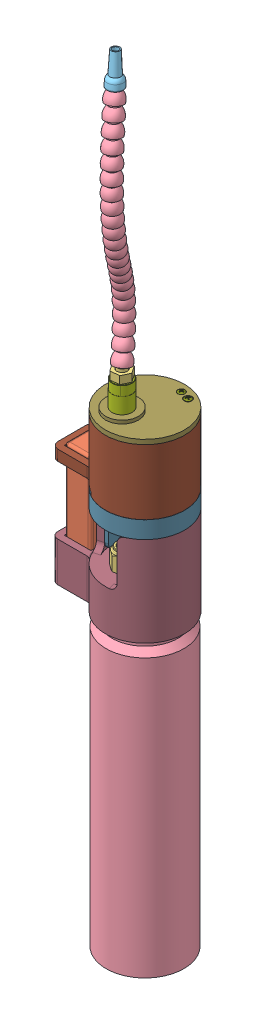
SolidWorks assembly _Robocup_Assembly_Wide_Straw_Water_Bottle_, configuration Default. Lengths in mm.
Overall size (108.2 768.91 103.62).
85 component instances, 35 part files, 77 mates.
Components (placement in the parent):
- SF3218MG Servo-1: SF3218MG Servo [Default] at (-17.653 -62.7888 -19.9) size (54.86 45.72 19.05)
- Servo gear 30t-1: Servo gear 30t [Default] at (-7.993 -20.4688 -10.375) x (-0.381225 0 -0.924482) z (0 1 0) size (25.51 25.6 6)
- Coolant Pipe.stp-1: Coolant Pipe.stp [Default] at (-8.06 46.6882 14.01) x (0.568385 0 0.822762) z (-0.822762 0 0.568385) size (74.23 300.91 26.18)
  - Coolant Bolt.stp-1: Coolant Bolt.stp [Default] x (-1 0 0) z (0 0 1) size (17.61 27.5 15.25)
  - Connectors.stp-1: Connectors.stp [Default] at (-2.2835 3.6671 -0.0362) x (-0.321951 -0.100327 -0.941426) z (0.285439 -0.958386 0.00452) size (18.3 18.3 20)
  - Connectors.stp-2: Connectors.stp [Default] at (-0.9485 62.1668 -0.2193) x (0.834188 -0.338799 0.435138) z (-0.378337 -0.925657 0.00458) size (18.3 18.3 20)
  - Connectors.stp-3: Connectors.stp [Default] at (-7.0218 39.1054 -0.1142) x (0.974617 -0.052931 0.217534) z (-0.054998 -0.99848 0.003454) size (18.3 18.3 20)
  - Connectors.stp-4: Connectors.stp [Default] at (-7.018 27.1423 -0.0887) x (-0.288884 -0.031731 -0.956838) z (0.11095 -0.993826 -0.00054) size (18.3 18.3 20)
  - Connectors.stp-5: Connectors.stp [Default] at (10.0914 83.4503 -0.3173) x (0.525964 -0.304704 -0.794051) z (-0.497138 -0.867664 0.003658) size (18.3 18.3 20)
  - Connectors.stp-6: Connectors.stp [Default] at (4.2645 72.9625 -0.2712) x (0.886562 -0.462353 0.015441) z (-0.462461 -0.88663 0.004202) size (18.3 18.3 20)
  - Connectors.stp-7: Connectors.stp [Default] at (-4.9174 50.8742 -0.1644) x (0.803108 -0.192004 0.56405) z (-0.235547 -0.971852 0.004557) size (18.3 18.3 20)
  - Connectors.stp-8: Connectors.stp [Default] at (16.0513 93.8656 -0.3564) x (0.86534 -0.495122 -0.077724) z (-0.496415 -0.86808 0.003062) size (18.3 18.3 20)
  - Connectors.stp-9: Connectors.stp [Default] at (35.5838 137.5772 -0.4345) x (0.770438 -0.236558 0.592002) z (-0.293738 -0.955886 0.000312) size (18.3 18.3 20)
  - Connectors.stp-10: Connectors.stp [Default] at (38.4122 149.228 -0.4322) x (0.672162 -0.141658 -0.726727) z (-0.20668 -0.978409 -0.000445) size (18.3 18.3 20)
  - Connectors.stp-11: Connectors.stp [Default] at (31.7619 126.2108 -0.4277) x (0.912958 -0.361121 0.189996) z (-0.368012 -0.929821 0.001063) size (18.3 18.3 20)
  - Connectors.stp-12: Connectors.stp [Default] at (21.8052 104.3949 -0.3882) x (-0.461711 0.244191 -0.852756) z (-0.471034 -0.882112 0.002437) size (18.3 18.3 20)
  - Connectors.stp-13: Connectors.stp [Default] at (-5.2287 15.2947 -0.0801) x (0.757626 0.173214 -0.629285) z (0.225426 -0.974255 0.003232) size (18.3 18.3 20)
  - Connectors.stp-14: Connectors.stp [Default] at (27.1083 115.1559 -0.4121) x (0.901968 -0.4265 -0.067469) z (-0.427365 -0.904078 0.001774) size (18.3 18.3 20)
  - Coolant Pipe Nozzle.stp-1: Coolant Pipe Nozzle.stp [Default] at (27.898 246.6708 -0.2231) x (-0.153795 -0.02183 0.987862) z (0.098368 -0.995128 -0.006677) size (15 15 30)
  - Connectors.stp-15: Connectors.stp [Default] at (40.4307 185.0487 -0.3789) x (0.938856 0.053217 -0.340172) z (0.055817 -0.998439 -0.002147) size (18.3 18.3 20)
  - Connectors.stp-16: Connectors.stp [Default] at (39.2092 196.9799 -0.3507) x (0.937442 0.118696 -0.327281) z (0.124773 -0.992182 -0.002445) size (18.3 18.3 20)
  - Connectors.stp-17: Connectors.stp [Default] at (40.784 173.0623 -0.4029) x (0.972219 -0.02226 -0.233011) z (-0.023301 -0.999727 -0.001718) size (18.3 18.3 20)
  - Connectors.stp-18: Connectors.stp [Default] at (40.1447 161.0902 -0.4212) x (0.882181 -0.100002 -0.460169) z (-0.113225 -0.993569 -0.001143) size (18.3 18.3 20)
  - Connectors.stp-19: Connectors.stp [Default] at (31.9646 232.2183 -0.2574) x (0.793284 0.199128 0.575369) z (0.245233 -0.969461 -0.002594) size (18.3 18.3 20)
  - Connectors.stp-20: Connectors.stp [Default] at (37.2637 208.8167 -0.3201) x (0.26581 0.051415 -0.962653) z (0.180811 -0.983514 -0.002604) size (18.3 18.3 20)
  - Connectors.stp-21: Connectors.stp [Default] at (28.861 243.8093 -0.2266) x (0.725081 0.197806 0.659645) z (0.26534 -0.964151 -0.002545) size (18.3 18.3 20)
  - Connectors.stp-22: Connectors.stp [Default] at (34.7978 220.5587 -0.2886) x (0.975424 0.217793 -0.033387) z (0.217828 -0.975984 -0.002632) size (18.3 18.3 20)
- Arduino Nano.STEP-1: Arduino Nano.STEP [Default] at (17.196 -13.0397 29.7784) x (0 -1 0) z (1 0 0) size (44.28 18 13.68)
  - ATMEGA328P-AU.STEP.STEP-1: ATMEGA328P-AU.STEP.STEP [Default] at (19.8219 24.4243 4.0882) x (-0.707107 -0.707107 0) z (0 0 1) size (9 9 1.2)
    - ATMEGA328P-AU--3DModel-STEP-56544.step.STEP.STEP.STEP.STEP-1: ATMEGA328P-AU--3DModel-STEP-56544.step.STEP.STEP.STEP.STEP [Default] at (2.8163 4.1 0.6768) x (1 0 0) z (0 -1 0) size (9 1.2 9)
  - Arduino Nano.STEP-1: Arduino Nano.STEP [Default] at (8.8551 11.9484 0) size (43.18 18 6.8)
  - Mini USB.STEP-1: Mini USB.STEP [Default] at (8.5451 19.5727 4.14) size (9.5 9.7 3.9)
  - CSTCE Crystal.STEP-1: CSTCE Crystal.STEP [Default] at (25.8562 23.1047 4.15) x (0.707107 -0.707107 0) z (0 0 1) size (3.2 1.35 0.71)
  - 2Pin Tactile Switch 6x3.6.STEP-1: 2Pin Tactile Switch 6x3.6.STEP [Default] at (30.7142 19.8184 4.14) x (0 1 0) z (0 0 1) size (7.9 3.6 2.2)
  - 0603 Resistor.STEP-1: 0603 Resistor.STEP [Default] at (34.4251 22.4184 4.14) size (1.6 0.8 0.5)
  - 0603 Resistor.STEP-2: 0603 Resistor.STEP [Default] at (34.4251 20.7184 4.14) size (1.6 0.8 0.5)
  - 0603 Resistor.STEP-3: 0603 Resistor.STEP [Default] at (34.4251 18.9184 4.14) size (1.6 0.8 0.5)
  - 0603 Resistor.STEP-4: 0603 Resistor.STEP [Default] at (34.4251 17.2184 4.14) size (1.6 0.8 0.5)
  - Blue LED.STEP-1: Blue LED.STEP [Default] at (37.0251 22.4184 4.14) size (1.6 0.8 0.6)
  - Green LED.STEP-1: Green LED.STEP [Default] at (37.0251 20.7184 4.14) size (1.6 0.8 0.6)
  - Red LED.STEP-1: Red LED.STEP [Default] at (37.0251 18.9184 4.14) size (1.6 0.8 0.6)
  - Blue LED.STEP-2: Blue LED.STEP [Default] at (37.0251 17.2184 4.14) size (1.6 0.8 0.6)
  - Header 2x3.STEP-1: Header 2x3.STEP [Default] at (45.6765 17.0321 4.14) x (0 1 0) z (0 0 1) size (7.62 5.07 10)
  - SOT89.STEP-1: SOT89.STEP [Default] at (38.4751 17.3184 0.94) x (0 1 0) z (0 0 1) size (6.5 7.1 1.6)
  - 1206 Tantalum.STEP-1: 1206 Tantalum.STEP [Default] at (38.6251 22.3684 2.54) x (-1 0 0) z (0 0 -1) size (3.2 1.6 1.5)
  - 0603 Resistor.STEP-5: 0603 Resistor.STEP [Default] at (38.4251 24.9684 2.54) x (-1 0 0) z (0 0 -1) size (1.6 0.8 0.5)
  - 0603 Capacitor.STEP-1: 0603 Capacitor.STEP [Default] at (35.0338 14.4684 2.54) x (-1 0 0) z (0 0 -1) size (1.6 0.8 0.7)
  - 1206 Tantalum.STEP-2: 1206 Tantalum.STEP [Default] at (7.6451 24.3684 2.54) x (1 0 0) z (0 0 -1) size (3.2 1.6 1.5)
  - 0603 Capacitor.STEP-2: 0603 Capacitor.STEP [Default] at (6.9059 22.4745 2.54) x (-1 0 0) z (0 0 -1) size (1.6 0.8 0.7)
  - 0603 Capacitor.STEP-3: 0603 Capacitor.STEP [Default] at (17.8451 14.0245 2.54) x (-1 0 0) z (0 0 -1) size (1.6 0.8 0.7)
  - 0603 Capacitor.STEP-4: 0603 Capacitor.STEP [Default] at (17.8451 15.0767 2.54) x (-1 0 0) z (0 0 -1) size (1.6 0.8 0.7)
  - 0603 Capacitor.STEP-5: 0603 Capacitor.STEP [Default] at (25.3451 21.2855 2.54) x (-1 0 0) z (0 0 -1) size (1.6 0.8 0.7)
  - 0603 Resistor.STEP-6: 0603 Resistor.STEP [Default] at (23.8451 15.8601 2.54) x (-1 0 0) z (0 0 -1) size (1.6 0.8 0.5)
  - 0603 Resistor.STEP-7: 0603 Resistor.STEP [Default] at (23.8451 14.4709 2.54) x (-1 0 0) z (0 0 -1) size (1.6 0.8 0.5)
  - CSTCE Crystal.STEP-2: CSTCE Crystal.STEP [Default] at (13.1731 14.7184 2.53) x (-1 0 0) z (0 0 -1) size (3.2 1.35 0.71)
  - SOIC16.STEP-1: SOIC16.STEP [Default] at (16.6451 19.5642 2.54) x (-1 0 0) z (0 0 -1) size (10.2 6 1.5)
- 5V Battery-1: 5V Battery [Default] at (-51.308 -152.7127 0) x (-1 0 0) z (0 0 -1) size (24.89 102.87 26.92)
- 5111K751_Push-to-Connect Tube Fitting for Air and Water-1: 5111K751_Push-to-Connect Tube Fitting for Air and Water [5111K751] at (-7.62 -156.8527 13.1982) x (0.904191 0 -0.427129) z (-0.427129 0 -0.904191) size (20.16 24.38 17.46)
- 5111K751_Push-to-Connect Tube Fitting for Air and Water-2: 5111K751_Push-to-Connect Tube Fitting for Air and Water [5111K751] at (-7.62 -107.9327 13.1982) x (-0.904191 0 0.427129) z (-0.427129 0 -0.904191) size (20.16 24.38 17.46)
- Water Bottle-1: Water Bottle [Default] at (0 -444.8127 0) size (74.93 304.8 74.93)
- Robocup_Shaft-1: Robocup_Shaft [Default] at (-8.06 -77.47 14.01) x (0.635001 0 0.772511) z (-0.772511 0 0.635001) size (20.32 97.79 20.32)
- Robocup_Bushing-3: Robocup_Bushing [6383K234] at (-8.06 -67.3013 14.01) x (-0.988739 0 0.149647) z (0 -1 0) size (31.75 31.75 11.13)
- Robocup_Straw_Adapter-1: Robocup_Straw_Adapter [Default] at (-8.06 17.8372 14.01) x (0 1 0) z (-0.635001 0 -0.772511) size (24.57 19.05 19.05)
- Robocup_Spacer-1: Robocup_Spacer [Default] at (-8.06 -60.9386 14.01) x (0.976941 0 0.21351) z (-0.21351 0 0.976941) size (19.05 40.47 19.05)
- Robocup_Shaft_Collar-1: Robocup_Shaft_Collar [top] at (-8.06 -1.7988 14.01) x (0.448618 0 0.893723) z (0.893723 0 -0.448618) size (19.05 12.32 19.05)
- Robocup_Motor_Mount-1: Robocup_Motor_Mount [Default] at (2.54 -40.9448 -9.95) x (0 0 -1) z (1 0 0) size (71.12 62.53 65.19)
- Robocup_Motor_Shield-1: Robocup_Motor_Shield [Default] at (0 -62.5348 0) size (108.2 62.78 76.2)
- Robocup_Motor_Top-2: Robocup_Motor_Top [Default] at origin size (76.2 7.62 76.2)
- Robocup_Lid_Wide_Straw_Water_Bottle-1: Robocup_Lid_Wide_Straw_Water_Bottle [Default] at (0 -165.4127 0) size (108.2 86.72 76.2)
- Robocup_Motor_Base_Wide_Straw-2: Robocup_Motor_Base_Wide_Straw [Default] at (0 -106.9848 0) size (76.2 63.87 76.2)
- Robocup_Gear-2: Robocup_Gear [Default] at (-8.06 -20.4678 14.01) x (-0.387559 0 -0.921845) z (0 1 0) size (25.51 25.6 6.35)
- 91802A146_Passivated 18-8 Stainless Steel Phillips Oval Head Screws-1: 91802A146_Passivated 18-8 Stainless Steel Phillips Oval Head Screws [91802A146] at (-21.59 -35.7677 -15.201) x (0 -1 0) z (-0.546944 0 0.837169) size (10.75 6.65 6.65)
- 91802A146_Passivated 18-8 Stainless Steel Phillips Oval Head Screws-2: 91802A146_Passivated 18-8 Stainless Steel Phillips Oval Head Screws [91802A146] at (13.65 -0.3175 -27.73) x (0 -1 0) z (-0.520208 0 0.85404) size (10.75 6.65 6.65)
- 91802A146_Passivated 18-8 Stainless Steel Phillips Oval Head Screws-3: 91802A146_Passivated 18-8 Stainless Steel Phillips Oval Head Screws [91802A146] at (26.67 -35.7677 -5.549) x (0 -1 0) z (-0.546944 0 0.837169) size (10.75 6.65 6.65)
- 91802A146_Passivated 18-8 Stainless Steel Phillips Oval Head Screws-4: 91802A146_Passivated 18-8 Stainless Steel Phillips Oval Head Screws [91802A146] at (22.6869 -16.0655 3.182) x (1 0 0) z (0 -0.752403 0.658703) size (10.75 6.65 6.65)
- 91802A146_Passivated 18-8 Stainless Steel Phillips Oval Head Screws-5: 91802A146_Passivated 18-8 Stainless Steel Phillips Oval Head Screws [91802A146] at (26.67 -35.7677 -15.201) x (0 -1 0) z (0 0 1) size (10.75 6.65 6.65)
- 91802A146_Passivated 18-8 Stainless Steel Phillips Oval Head Screws-6: 91802A146_Passivated 18-8 Stainless Steel Phillips Oval Head Screws [91802A146] at (4.445 -63.4873 -30.48) x (0 -1 0) z (0 0 1) size (10.75 6.65 6.65)
- 91802A146_Passivated 18-8 Stainless Steel Phillips Oval Head Screws-7: 91802A146_Passivated 18-8 Stainless Steel Phillips Oval Head Screws [91802A146] at (-4.445 -63.4873 -30.48) x (0 -1 0) z (-0.546944 0 0.837169) size (10.75 6.65 6.65)
- 91802A146_Passivated 18-8 Stainless Steel Phillips Oval Head Screws-8: 91802A146_Passivated 18-8 Stainless Steel Phillips Oval Head Screws [91802A146] at (-21.59 -35.7677 -5.549) x (0 -1 0) z (0 0 1) size (10.75 6.65 6.65)
- 91802A146_Passivated 18-8 Stainless Steel Phillips Oval Head Screws-9: 91802A146_Passivated 18-8 Stainless Steel Phillips Oval Head Screws [91802A146] at (4.76 -0.3175 -30.27) x (0 -1 0) z (-0.999956 0 -0.009425) size (10.75 6.65 6.65)
- 91802A146_Passivated 18-8 Stainless Steel Phillips Oval Head Screws-11: 91802A146_Passivated 18-8 Stainless Steel Phillips Oval Head Screws [91802A146] at (-13.7901 -6.2438 16.8863) x (0.893723 0 -0.448618) z (-0.414893 -0.380394 -0.826538) size (10.75 6.65 6.65)
- 90480A007_Low-Strength Steel Hex Nut-1: 90480A007_Low-Strength Steel Hex Nut [90480A007] at (13.65 -3.9291 -27.73) x (0.931587 0 0.363518) z (-0.363518 0 0.931587) size (7.94 3.39 9.17)
- 90480A007_Low-Strength Steel Hex Nut-2: 90480A007_Low-Strength Steel Hex Nut [90480A007] at (4.76 -3.9291 -30.27) x (0.772389 0 -0.635149) z (0.635149 0 0.772389) size (7.94 3.39 9.17)
- 90480A007_Low-Strength Steel Hex Nut-3: 90480A007_Low-Strength Steel Hex Nut [90480A007] at (4.445 -67.0989 -30.48) size (7.94 3.39 9.17)
- 90480A007_Low-Strength Steel Hex Nut-4: 90480A007_Low-Strength Steel Hex Nut [90480A007] at (-4.445 -67.0989 -30.48) size (7.94 3.39 9.17)
Mates (geometry in assembly coordinates):
- Concentric6: concentric aligned: cylinder of robocup hollow shaft midfi-1 through (-8.06 20.32 14.01) axis (0 -1 0) radius 6.096; cylinder of Robocup bushing-3 through (-8.06 -72.0638 14.01) axis (0 -1 0) radius 6.35
- Concentric7: concentric anti-aligned: cylinder of robocup hollow shaft midfi-1 through (-8.06 20.32 14.01) axis (0 -1 0) radius 6.096; cylinder of shaft to fourth npt female midfi-1 through (-8.06 7.62 14.01) axis (0 1 0) radius 6.223
- Coincident13: coincident anti-aligned: plane of robocup hollow shaft midfi-1 through (-14.0482 20.32 17.2883) normal (0.635001 0 0.772511); plane of shaft to fourth npt female midfi-1 through (-12.7908 7.62 16.2547) normal (-0.635001 0 -0.772511)
- Coincident15: coincident anti-aligned: plane of robocup hollow shaft midfi-1 through (-8.06 20.32 14.01) normal (0 1 0); plane of shaft to fourth npt female midfi-1 through (-8.06 20.32 14.01) normal (0 -1 0)
- Concentric10: concentric aligned: cylinder of robocup hollow shaft midfi-1 through (-8.06 20.32 14.01) axis (0 -1 0) radius 6.096; cylinder of Robocup_Spacer-1 through (-8.06 -20.4678 14.01) axis (0 -1 0) radius 9.525
- Concentric12: concentric anti-aligned: cylinder of robocup hollow shaft midfi-1 through (-8.06 20.32 14.01) axis (0 -1 0) radius 6.096; cylinder of Robocup_Shaft_Collar-1 through (-8.06 -6.2438 14.01) axis (0 1 0) radius 9.525
- Concentric55: concentric aligned: circle of shaft to fourth npt female-1; circle of Coolant Pipe.stp-1/Coolant Bolt.stp-1
- Coincident109: coincident anti-aligned: plane of shaft to fourth npt female midfi-1 through (-8.06 32.1882 14.01) normal (0 1 0); plane of Coolant Pipe.stp-1/Coolant Bolt.stp-1 through (-8.06 32.1882 14.01) normal (0 -1 0)
- Coincident115: coincident anti-aligned: plane of Robocup Top Plate lowfi-2 through (0 0 0) normal (0 -1 0); plane of Robocup_Motor_Mount-1 through (0 0 0) normal (0 1 0)
- Coincident117: coincident anti-aligned: plane of Robocup_Motor_Shield-1 through (0 0 0) normal (0 1 0); plane of Robocup Top Plate lowfi-2 through (0 0 0) normal (0 -1 0)
- Coincident127: coincident anti-aligned: plane of Robocup bushing-3 through (-9.2963 -60.9386 5.8417) normal (0 1 0); plane of Robocup_Spacer-1 through (-8.06 -60.9386 14.01) normal (0 -1 0)
- Coincident131: coincident anti-aligned: plane of Robocup_Motor_Mount-1 through (21.336 22.5049 2.21) normal (-1 0 0); plane of Arduino Nano.STEP-1/Arduino Nano.STEP-1 through (21.336 -21.8948 17.83) normal (1 0 0)
- Coincident133: coincident anti-aligned: plane of Robocup_Motor_Mount-1 through (21.336 22.5049 1.21) normal (0 0 1); plane of Arduino Nano.STEP-1/Arduino Nano.STEP-1 through (21.336 -18.0848 1.21) normal (0 0 -1)
- Parallel1: parallel anti-aligned: plane of Robocup_Motor_Shield-1 through (0 -62.5348 0) normal (1 0 0); plane of Robocup_Motor_Mount-1 through (-29.4704 -62.5348 0) normal (-1 0 0)
- Coincident136: coincident aligned: plane of Robocup Top Plate lowfi-2 through (0 0 0) normal (0 0 1)
- Coincident137: coincident aligned: plane of Robocup Top Plate lowfi-2 through (0 0 0) normal (1 0 0)
- Coincident138: coincident aligned: plane of Robocup Top Plate lowfi-2 through (0 0 0) normal (0 1 0)
- Concentric77: concentric anti-aligned: cylinder of Robocup_Motor_Mount-1 through (0 -62.5348 0) axis (0 1 0) radius 35.56; cylinder of Robocup_Motor_Shield-1 through (0 0 0) axis (0 -1 0) radius 38.1
- Parallel6: parallel aligned: plane of Robocup_Motor_Mount-1 through (2.54 -40.9448 -9.95) normal (1 0 0)
- Concentric78: concentric aligned: cylinder of SF3218MG Servo-1 through (-7.993 39.4275 -10.375) axis (0 -1 0) radius 3.81; cylinder of Servo gear 30t-1 through (-7.993 11.0983 -10.375) axis (0 -1 0) radius 3.85
- Coincident165: coincident anti-aligned: plane of SF3218MG Servo-1 through (-17.653 -62.7888 -19.9) normal (0 0 -1); plane of Robocup_Motor_Mount-1 through (-17.78 -35.8648 -19.9) normal (0 0 1)
- Coincident166: coincident anti-aligned: plane of SF3218MG Servo-1 through (-17.653 -35.8648 -27.7545) normal (0 -1 0); plane of Robocup_Motor_Mount-1 through (2.54 -35.8648 -9.95) normal (0 1 0)
- Coincident168: coincident anti-aligned: plane of SF3218MG Servo-1 through (-17.653 -17.0688 -0.85) normal (0 1 0); plane of Servo gear 30t-1 through (-7.993 -17.0688 -10.375) normal (0 -1 0)
- Concentric79: concentric anti-aligned: cylinder of Robocup_Lid_Wide_Straw_Water_Bottle-1 through (0 -165.4127 0) axis (0 -1 0) radius 38.1; cylinder of Robocup_Motor_Base_Wide_Straw-2 through (0 -186.8158 0) axis (0 1 0) radius 38.1
- Coincident170: coincident aligned: plane of Robocup_Lid_Wide_Straw_Water_Bottle-1 through (0 -165.4127 0) normal (1 0 0); plane of Robocup_Motor_Base_Wide_Straw-2 through (0 -106.9848 0) normal (1 0 0)
- Coincident171: coincident aligned: plane of Robocup_Lid_Wide_Straw_Water_Bottle-1 through (0 -165.4127 0) normal (1 0 0)
- Coincident172: coincident aligned: plane of Robocup_Lid_Wide_Straw_Water_Bottle-1 through (0 -165.4127 0) normal (0 0 1)
- Concentric84: concentric anti-aligned: cylinder of Robocup_Motor_Mount-1 through (0 -62.5348 0) axis (0 1 0) radius 35.56; cylinder of Robocup_Lid_Wide_Straw_Water_Bottle-1 through (0 -165.4127 0) axis (0 -1 0) radius 38.1
- Coincident175: coincident anti-aligned: plane of Robocup bushing-3 through (-9.664 -64.0628 3.4119) normal (0 -1 0); plane of Robocup_Motor_Base_Wide_Straw-2 through (-1.0936 -64.0628 1.9012) normal (0 1 0)
- Coincident178: coincident anti-aligned: plane of 5V Battery-1 through (-51.308 -152.7127 0) normal (0 0 -1)
- Coincident180: coincident anti-aligned: plane of 5V Battery-1 through (-63.754 -49.8427 13.462) normal (-1 0 0); plane of Robocup_Lid_Wide_Straw_Water_Bottle-1 through (-63.754 -71.9998 13.843) normal (1 0 0)
- Coincident181: coincident anti-aligned: plane of Robocup_Lid_Wide_Straw_Water_Bottle-1 through (0 -126.0427 0) normal (0 1 0); plane of Robocup_Motor_Base_Wide_Straw-2 through (0 -126.0427 0) normal (0 -1 0)
- Coincident187: coincident anti-aligned: plane of Robocup_Motor_Mount-1 through (2.54 -61.2648 -9.95) normal (0 1 0); plane of Arduino Nano.STEP-1/Arduino Nano.STEP-1 through (21.336 -61.2648 1.21) normal (0 -1 0)
- Concentric90: concentric aligned: cylinder of robocup hollow shaft midfi-1 through (-8.06 20.32 14.01) axis (0 -1 0) radius 6.096; cylinder of robocup straw gear 30t-2 through (-8.06 -14.4678 14.01) axis (0 -1 0) radius 6.223
- Coincident188: coincident anti-aligned: plane of Robocup_Spacer-1 through (-8.06 -20.4678 14.01) normal (0 1 0); plane of robocup straw gear 30t-2 through (-19.297 -20.4678 19.2561) normal (0 -1 0)
- Coincident190: coincident anti-aligned: plane of Robocup_Motor_Mount-1 through (2.54 -62.5348 -9.95) normal (0 -1 0); plane of Robocup_Motor_Base_Wide_Straw-2 through (0 -62.5348 0) normal (0 1 0)
- Coincident191: coincident anti-aligned: plane of Robocup_Shaft_Collar-1 through (-8.06 -14.1178 14.01) normal (0 -1 0); plane of robocup straw gear 30t-2 through (-2.7381 -14.1178 24.9065) normal (0 1 0)
- Distance1: distance = 0.635 mm anti-aligned: plane of SF3218MG Servo-1 through (22.733 -62.7888 -0.85) normal (1 0 0); plane of robocup servo mount mid-fi-1 through (23.368 -62.5348 0) normal (-1 0 0)
- Concentric92: concentric aligned: cylinder of Robocup Top Plate lowfi-2 through (13.65 0 -27.73) axis (0 1 0) radius 1.778; circle of 91802A146_Passivated 18-8 Stainless Steel Phillips Oval Head Screws-2
- Coincident193: coincident aligned: plane of Robocup Top Plate lowfi-2 through (0 4.445 0) normal (0 1 0); circle of 91802A146_Passivated 18-8 Stainless Steel Phillips Oval Head Screws-2
- Concentric94: concentric aligned: circle of 91802A146_Passivated 18-8 Stainless Steel Phillips Oval Head Screws-9; circle of Robocup Top Plate midfi-2
- Coincident194: coincident aligned: plane of Robocup Top Plate lowfi-2 through (0 4.445 0) normal (0 1 0); circle of 91802A146_Passivated 18-8 Stainless Steel Phillips Oval Head Screws-9
- Concentric95: concentric anti-aligned: cylinder of Robocup_Motor_Mount-1 through (4.445 -37.1348 -30.48) axis (0 -1 0) radius 2.032; circle of 91802A146_Passivated 18-8 Stainless Steel Phillips Oval Head Screws-6
- Coincident195: coincident aligned: plane of Robocup_Motor_Mount-1 through (2.54 -58.7248 -9.95) normal (0 1 0); circle of 91802A146_Passivated 18-8 Stainless Steel Phillips Oval Head Screws-6
- Concentric96: concentric anti-aligned: cylinder of Robocup_Motor_Mount-1 through (-4.445 -37.1348 -30.48) axis (0 -1 0) radius 2.032; circle of 91802A146_Passivated 18-8 Stainless Steel Phillips Oval Head Screws-7
- Coincident196: coincident aligned: plane of Robocup_Motor_Mount-1 through (2.54 -58.7248 -9.95) normal (0 1 0); circle of 91802A146_Passivated 18-8 Stainless Steel Phillips Oval Head Screws-7
- Concentric97: concentric aligned: cylinder of SF3218MG Servo-1 through (-21.59 -62.7888 -15.201) axis (0 1 0) radius 2.54; circle of 91802A146_Passivated 18-8 Stainless Steel Phillips Oval Head Screws-1
- Coincident197: coincident aligned: plane of SF3218MG Servo-1 through (-17.653 -32.8168 -27.7545) normal (0 1 0); circle of 91802A146_Passivated 18-8 Stainless Steel Phillips Oval Head Screws-1
- Coincident198: coincident aligned: plane of SF3218MG Servo-1 through (-17.653 -32.8168 -27.7545) normal (0 1 0); circle of 91802A146_Passivated 18-8 Stainless Steel Phillips Oval Head Screws-8
- Concentric98: concentric aligned: cylinder of SF3218MG Servo-1 through (-21.59 -62.7888 -5.549) axis (0 1 0) radius 2.54; circle of 91802A146_Passivated 18-8 Stainless Steel Phillips Oval Head Screws-8
- Coincident199: coincident aligned: plane of SF3218MG Servo-1 through (22.733 -32.8168 -27.7545) normal (0 1 0); circle of 91802A146_Passivated 18-8 Stainless Steel Phillips Oval Head Screws-5
- Concentric99: concentric aligned: cylinder of SF3218MG Servo-1 through (26.67 -62.7888 -15.201) axis (0 1 0) radius 2.54; circle of 91802A146_Passivated 18-8 Stainless Steel Phillips Oval Head Screws-5
- Concentric100: concentric aligned: circle of SF3218MG Servo-1; circle of 91802A146_Passivated 18-8 Stainless Steel Phillips Oval Head Screws-3
- Coincident200: coincident aligned: plane of SF3218MG Servo-1 through (22.733 -32.8168 -27.7545) normal (0 1 0); circle of 91802A146_Passivated 18-8 Stainless Steel Phillips Oval Head Screws-3
- Concentric101: concentric aligned: cylinder of Robocup_Motor_Mount-1 through (34.4929 -16.0655 3.182) axis (-1 0 0) radius 1.778; circle of 91802A146_Passivated 18-8 Stainless Steel Phillips Oval Head Screws-4
- Coincident201: coincident aligned: plane of Arduino Nano.STEP-1/Arduino Nano.STEP-1 through (19.736 -21.8948 17.83) normal (-1 0 0); circle of 91802A146_Passivated 18-8 Stainless Steel Phillips Oval Head Screws-4
- Concentric106: concentric anti-aligned: cylinder of Robocup_Shaft_Collar-1 through (-16.5727 -6.2438 18.2831) axis (0.893723 0 -0.448618) radius 1.7145; circle of 91802A146_Passivated 18-8 Stainless Steel Phillips Oval Head Screws-11
- Tangent9: tangent: cylinder of Robocup_Shaft_Collar-1 through (-8.06 -6.2438 14.01) axis (0 1 0) radius 9.525; circle of 91802A146_Passivated 18-8 Stainless Steel Phillips Oval Head Screws-11
- Concentric107: concentric aligned: cylinder of robocup hollow shaft midfi-1 through (-8.06 20.32 14.01) axis (0 -1 0) radius 6.096; cylinder of Robocup Top Plate lowfi-2 through (-8.06 7.62 14.01) axis (0 -1 0) radius 6.35
- Coincident202: coincident anti-aligned: plane of shaft to fourth npt female midfi-1 through (-8.06 7.62 14.01) normal (0 -1 0); plane of Robocup Top Plate lowfi-2 through (-8.06 7.62 14.01) normal (0 1 0)
- Coincident203: coincident anti-aligned: plane of Robocup_Motor_Mount-1 through (2.54 -2.54 -9.95) normal (0 -1 0); plane of 90480A007_Low-Strength Steel Hex Nut-1 through (10.7857 -2.54 -31.3073) normal (0 1 0)
- Coincident204: coincident anti-aligned: plane of Robocup_Motor_Mount-1 through (2.54 -2.54 -9.95) normal (0 -1 0); plane of 90480A007_Low-Strength Steel Hex Nut-2 through (0.2392 -2.54 -29.5191) normal (0 1 0)
- Concentric109: concentric anti-aligned: circle of Robocup Top Plate lowfi-2; circle of 90480A007_Low-Strength Steel Hex Nut-2
- Concentric110: concentric aligned: circle of 91802A146_Passivated 18-8 Stainless Steel Phillips Oval Head Screws-2; circle of 90480A007_Low-Strength Steel Hex Nut-1
- Parallel9: parallel anti-aligned: plane of Robocup_Motor_Mount-1 through (21.9136 -8.89 -35.8592) normal (-0.931587 0 -0.363518); plane of 90480A007_Low-Strength Steel Hex Nut-1 through (16.5143 -2.54 -24.1527) normal (0.931587 0 0.363518)
- Parallel10: parallel anti-aligned: plane of Robocup_Motor_Mount-1 through (1.82 -8.89 -34.2344) normal (0.93625 0 0.351334); plane of 90480A007_Low-Strength Steel Hex Nut-2 through (1.8493 -2.54 -33.8096) normal (-0.93625 0 -0.351334)
- Coincident205: coincident anti-aligned: plane of Robocup_Motor_Base_Wide_Straw-2 through (0 -65.7098 0) normal (0 -1 0); plane of 90480A007_Low-Strength Steel Hex Nut-4 through (-8.4137 -65.7098 -32.7714) normal (0 1 0)
- Coincident206: coincident anti-aligned: plane of Robocup_Motor_Base_Wide_Straw-2 through (0 -65.7098 0) normal (0 -1 0); plane of 90480A007_Low-Strength Steel Hex Nut-3 through (0.4763 -65.7098 -32.7714) normal (0 1 0)
- Concentric112: concentric anti-aligned: circle of motorbox bottom low-fi-1; circle of 90480A007_Low-Strength Steel Hex Nut-3
- Concentric113: concentric anti-aligned: circle of motorbox bottom low-fi-1; circle of 90480A007_Low-Strength Steel Hex Nut-4
- Concentric114: concentric aligned: cylinder of Robocup_Lid_Wide_Straw_Water_Bottle-1 through (0 -165.4127 0) axis (0 -1 0) radius 38.1; cylinder of Water Bottle-1 through (0 -444.8127 0) axis (0 -1 0) radius 37.465
- Coincident207: coincident anti-aligned: plane of Robocup_Lid_Wide_Straw_Water_Bottle-1 through (31.75 -140.0127 0) normal (0 -1 0); plane of Water Bottle-1 through (31.75 -140.0127 0) normal (0 1 0)
- Coincident208: coincident anti-aligned: plane of 5V Battery-1 through (-51.308 -152.7127 0) normal (0 -1 0); plane of Robocup_Lid_Wide_Straw_Water_Bottle-1 through (0 -152.7127 0) normal (0 1 0)
- Coincident209: coincident anti-aligned: plane of Robocup_Lid_Wide_Straw_Water_Bottle-1 through (0 -126.0427 0) normal (0 1 0); plane of 5111K751_Push-to-Connect Tube Fitting for Air and Water-2 through (-7.62 -126.0427 13.1982) normal (0 -1 0)
- Concentric115: concentric aligned: cylinder of Robocup_Lid_Wide_Straw_Water_Bottle-1 through (-7.62 -165.4127 13.1982) axis (0 1 0) radius 3.175; cylinder of 5111K751_Push-to-Connect Tube Fitting for Air and Water-2 through (-7.62 -107.9327 13.1982) axis (0 1 0) radius 5.515
- Coincident210: coincident anti-aligned: plane of 5111K751_Push-to-Connect Tube Fitting for Air and Water-1 through (-7.62 -138.7427 13.1982) normal (0 1 0); plane of Robocup_Lid_Wide_Straw_Water_Bottle-1 through (0 -138.7427 0) normal (0 -1 0)
- Concentric116: concentric anti-aligned: cylinder of 5111K751_Push-to-Connect Tube Fitting for Air and Water-1 through (-7.62 -156.8527 13.1982) axis (0 -1 0) radius 7.075; cylinder of Robocup_Lid_Wide_Straw_Water_Bottle-1 through (-7.62 -165.4127 13.1982) axis (0 1 0) radius 3.175
